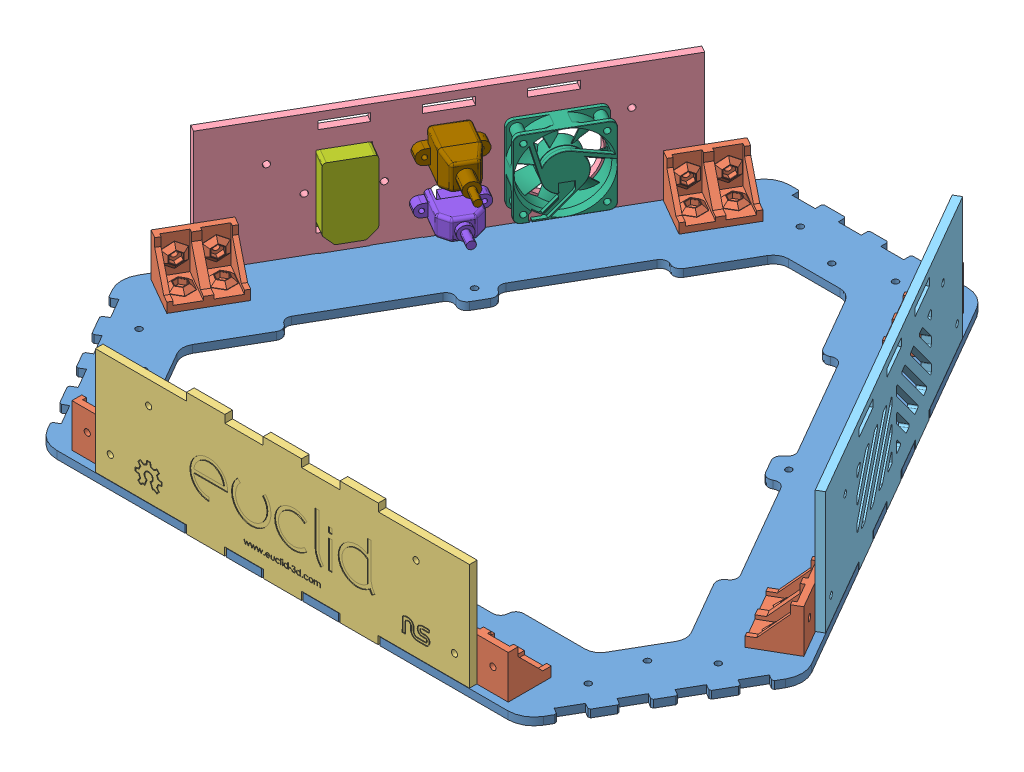
SolidWorks assembly bottom-assembly, configuration Default. Lengths in mm.
Overall size (489.42 85 494.01).
14 component instances, 9 part files, 42 mates.
Components (placement in the parent):
- acrylic-bottom-1: acrylic-bottom [Default] x (0 0 -1) z (1 0 0) size (388.46 5 443.29)
- window-bracket-dual-1: window-bracket-dual [Default] at (-122.1346 0 211.5433) x (0 0 -1) z (1 0 0) size (48.64 28 44.25)
- window-bracket-dual-2: window-bracket-dual [Default] x (0 0 -1) z (1 0 0) size (48.64 28 44.25)
- window-bracket-dual-3: window-bracket-dual [Default] x (0.866025 0 0.5) z (-0.5 0 0.866025) size (48.64 28 44.25)
- window-bracket-dual-4: window-bracket-dual [Default] at (-122.1346 0 -211.5433) x (0.866025 0 0.5) z (-0.5 0 0.866025) size (48.64 28 44.25)
- window-bracket-dual-5: window-bracket-dual [Default] at (244.2691 0 0) x (-0.866025 0 0.5) z (-0.5 0 -0.866025) size (48.64 28 44.25)
- window-bracket-dual-6: window-bracket-dual [Default] x (-0.866025 0 0.5) z (-0.5 0 -0.866025) size (48.64 28 44.25)
- acrylic-pscover-1: acrylic-pscover [Default] at (0 0 331.9134) x (0.866025 0 -0.5) z (0.5 0 0.866025) size (213.61 80 126.21)
- acrylic-switch-cover-1: acrylic-switch-cover [Default] x (0 0 -1) z (1 0 0) size (213.61 85 126.21)
- acrylic-bay-cover-1: acrylic-bay-cover [Default] x (0.866025 0 0.5) z (-0.5 0 0.866025) size (213.61 85 126.21)
- 50mm-fan-1: 50mm-fan [Default] at (-102.8673 -54.875 -118.7421) x (0 1 0) z (-0.5 0 0.866025) size (50.23 15.09 50)
- power-switch-1: power-switch [Default] at (-173.0529 -54.875 -42.1771) x (0.5 0 -0.866025) z (0 1 0) size (49.3 24.57 58)
- usb-b2b-extension-1: usb-b2b-extension [Default] at (-134.846 -69.75 -77.8534) x (-0.5 0 0.866025) z (-0.866025 0 -0.5) size (38 13.5 40)
- ethernet-extension-1: ethernet-extension [Default] at (-143.0732 -40 -82.6034) x (0.5 0 -0.866025) z (-0.866025 0 -0.5) size (36.4 22.5 53.25)
Mates (geometry in assembly coordinates):
- Coincident1: coincident anti-aligned: plane of acrylic-bottom-1 through (0 -90 0) normal (0 1 0); plane of window-bracket-dual-1 through (-185.75 -90 174.8149) normal (0 -1 0)
- Concentric1: concentric anti-aligned: cylinder of acrylic-bottom-1 through (-184.6346 -95 22.883) axis (0 1 0) radius 2; cylinder of window-bracket-dual-1 through (-184.6346 74.864 22.883) axis (0 -1 0) radius 2
- Concentric2: concentric anti-aligned: cylinder of acrylic-bottom-1 through (-194.6346 -95 40.2035) axis (0 1 0) radius 2; cylinder of window-bracket-dual-1 through (-194.6346 74.864 40.2035) axis (0 -1 0) radius 2
- Coincident2: coincident anti-aligned: plane of acrylic-bottom-1 through (0 -90 0) normal (0 1 0); plane of window-bracket-dual-2 through (-63.6154 -90 -36.7284) normal (0 -1 0)
- Concentric3: concentric anti-aligned: cylinder of acrylic-bottom-1 through (-62.5 -95 -188.6603) axis (0 1 0) radius 2; cylinder of window-bracket-dual-2 through (-62.5 74.864 -188.6603) axis (0 -1 0) radius 2
- Concentric4: concentric anti-aligned: cylinder of acrylic-bottom-1 through (-72.5 -95 -171.3397) axis (0 1 0) radius 2; cylinder of window-bracket-dual-2 through (-72.5 74.864 -171.3397) axis (0 -1 0) radius 2
- Coincident3: coincident anti-aligned: plane of acrylic-bottom-1 through (0 -90 0) normal (0 1 0); plane of window-bracket-dual-4 through (-58.5192 -90 -248.2716) normal (0 -1 0)
- Concentric5: concentric anti-aligned: cylinder of acrylic-bottom-1 through (72.5 -95 -171.3397) axis (0 1 0) radius 2; cylinder of window-bracket-dual-4 through (72.5 74.864 -171.3397) axis (0 -1 0) radius 2
- Concentric6: concentric anti-aligned: cylinder of acrylic-bottom-1 through (62.5 -95 -188.6603) axis (0 1 0) radius 2; cylinder of window-bracket-dual-4 through (62.5 74.864 -188.6603) axis (0 -1 0) radius 2
- Coincident4: coincident anti-aligned: plane of acrylic-bottom-1 through (0 -90 0) normal (0 1 0); plane of window-bracket-dual-3 through (63.6154 -90 -36.7284) normal (0 -1 0)
- Concentric7: concentric anti-aligned: cylinder of acrylic-bottom-1 through (194.6346 -95 40.2035) axis (0 1 0) radius 2; cylinder of window-bracket-dual-3 through (194.6346 74.864 40.2035) axis (0 -1 0) radius 2
- Concentric8: concentric anti-aligned: cylinder of acrylic-bottom-1 through (184.6346 -95 22.883) axis (0 1 0) radius 2; cylinder of window-bracket-dual-3 through (184.6346 74.864 22.883) axis (0 -1 0) radius 2
- Coincident5: coincident anti-aligned: plane of acrylic-bottom-1 through (0 -90 0) normal (0 1 0); plane of window-bracket-dual-5 through (244.2691 -90 73.4567) normal (0 -1 0)
- Concentric9: concentric anti-aligned: cylinder of acrylic-bottom-1 through (112.1346 -95 148.4567) axis (0 1 0) radius 2; cylinder of window-bracket-dual-5 through (112.1346 74.864 148.4567) axis (0 -1 0) radius 2
- Concentric10: concentric anti-aligned: cylinder of acrylic-bottom-1 through (132.1346 -95 148.4567) axis (0 1 0) radius 2; cylinder of window-bracket-dual-5 through (132.1346 74.864 148.4567) axis (0 -1 0) radius 2
- Coincident6: coincident anti-aligned: plane of acrylic-bottom-1 through (0 -90 0) normal (0 1 0); plane of window-bracket-dual-6 through (0 -90 73.4567) normal (0 -1 0)
- Concentric11: concentric anti-aligned: cylinder of acrylic-bottom-1 through (-112.1346 -95 148.4567) axis (0 1 0) radius 2; cylinder of window-bracket-dual-6 through (-112.1346 74.864 148.4567) axis (0 -1 0) radius 2
- Concentric12: concentric anti-aligned: cylinder of acrylic-bottom-1 through (-132.1346 -95 148.4567) axis (0 1 0) radius 2; cylinder of window-bracket-dual-6 through (-132.1346 74.864 148.4567) axis (0 -1 0) radius 2
- Coincident8: coincident aligned: plane of acrylic-bottom-1; plane of assembly through (0 0 0) normal (0 1 0)
- Coincident10: coincident anti-aligned: plane of acrylic-bottom-1 through (0 0 0) normal (0 0 -1); plane of assembly through (0 0 0) normal (0 0 1)
- Coincident11: coincident aligned: plane of acrylic-bottom-1 through (0 0 0) normal (1 0 0); plane of assembly through (0 0 0) normal (1 0 0)
- Coincident12: coincident anti-aligned: plane of window-bracket-dual-5 through (244.2691 0 163.4567) normal (0 0 1); plane of acrylic-pscover-1 through (0 0 163.4567) normal (0 0 -1)
- Concentric13: concentric aligned: cylinder of window-bracket-dual-5 through (112.1346 -75 -1.4073) axis (0 0 1) radius 2; cylinder of acrylic-pscover-1 through (112.1346 -75 95.5709) axis (0 0 1) radius 2
- Concentric14: concentric aligned: cylinder of window-bracket-dual-6 through (-112.1346 -75 -1.4073) axis (0 0 1) radius 2; cylinder of acrylic-pscover-1 through (-112.1346 -75 95.5709) axis (0 0 1) radius 2
- Coincident13: coincident anti-aligned: plane of window-bracket-dual-3 through (141.5577 0 -81.7284) normal (0.866025 0 -0.5); plane of acrylic-bay-cover-1 through (141.5577 0 -81.7284) normal (-0.866025 0 0.5)
- Concentric15: concentric anti-aligned: cylinder of window-bracket-dual-4 through (-57.286 -75 -96.4077) axis (0.866025 0 -0.5) radius 2; cylinder of acrylic-bay-cover-1 through (148.6114 -75 -215.2827) axis (-0.866025 0 0.5) radius 2
- Concentric16: concentric anti-aligned: cylinder of window-bracket-dual-3 through (54.8485 -75 97.815) axis (0.866025 0 -0.5) radius 2; cylinder of acrylic-bay-cover-1 through (260.7459 -75 -21.0599) axis (-0.866025 0 0.5) radius 2
- Coincident14: coincident anti-aligned: plane of window-bracket-dual-2 through (-141.5577 0 -81.7284) normal (-0.866025 0 -0.5); plane of acrylic-switch-cover-1 through (-141.5577 0 -81.7284) normal (0.866025 0 0.5)
- Concentric17: concentric anti-aligned: cylinder of window-bracket-dual-2 through (57.286 -75 -96.4077) axis (-0.866025 0 -0.5) radius 2; cylinder of acrylic-switch-cover-1 through (-148.6114 -75 -215.2827) axis (0.866025 0 0.5) radius 2
- Concentric18: concentric anti-aligned: cylinder of window-bracket-dual-1 through (-54.8485 -75 97.815) axis (-0.866025 0 -0.5) radius 2; cylinder of acrylic-switch-cover-1 through (-260.7459 -75 -21.0599) axis (0.866025 0 0.5) radius 2
- Coincident15: coincident anti-aligned: plane of acrylic-switch-cover-1 through (-141.5577 0 -81.7284) normal (0.866025 0 0.5); plane of 50mm-fan-1 through (-103.3577 -79.875 -147.8927) normal (-0.866025 0 -0.5)
- Concentric19: concentric anti-aligned: cylinder of acrylic-switch-cover-1 through (-34.4442 -34.875 -56.144) axis (-0.866025 0 -0.5) radius 1.6; cylinder of 50mm-fan-1 through (-130.3892 -34.875 -111.5379) axis (0.866025 0 0.5) radius 1.85
- Concentric21: concentric anti-aligned: cylinder of acrylic-switch-cover-1 through (-14.4442 -74.875 -90.785) axis (-0.866025 0 -0.5) radius 1.6; cylinder of 50mm-fan-1 through (-110.3892 -74.875 -146.1789) axis (0.866025 0 0.5) radius 1.85
- Concentric22: concentric aligned: cylinder of acrylic-switch-cover-1 through (-84.6942 -54.875 30.8916) axis (-0.866025 0 -0.5) radius 2; cylinder of power-switch-1 through (-180.4378 -54.875 -24.386) axis (-0.866025 0 -0.5) radius 2
- Concentric23: concentric aligned: cylinder of acrylic-switch-cover-1 through (-65.5942 -54.875 -2.1906) axis (-0.866025 0 -0.5) radius 2; cylinder of power-switch-1 through (-161.3378 -54.875 -57.4682) axis (-0.866025 0 -0.5) radius 2
- Coincident17: coincident anti-aligned: plane of acrylic-switch-cover-1 through (-145.8878 0 -84.2284) normal (-0.866025 0 -0.5); plane of power-switch-1 through (-170.8878 -54.875 -40.9271) normal (0.866025 0 0.5)
- Coincident18: coincident anti-aligned: plane of acrylic-switch-cover-1 through (-141.5577 0 -81.7284) normal (0.866025 0 0.5); plane of usb-b2b-extension-1 through (-151.0577 -63 -65.2739) normal (-0.866025 0 -0.5)
- Coincident19: coincident anti-aligned: plane of acrylic-switch-cover-1 through (-141.5577 0 -81.7284) normal (0.866025 0 0.5); plane of ethernet-extension-1 through (-148.3077 -40 -70.037) normal (-0.866025 0 -0.5)
- Concentric31: concentric aligned: cylinder of acrylic-switch-cover-1 through (-42.6442 -69.75 -41.9412) axis (-0.866025 0 -0.5) radius 1.6; cylinder of usb-b2b-extension-1 through (-111.108 -69.75 -81.4687) axis (-0.866025 0 -0.5) radius 1.5
- Concentric32: concentric aligned: cylinder of acrylic-switch-cover-1 through (-57.6442 -69.75 -15.9604) axis (-0.866025 0 -0.5) radius 1.6; cylinder of usb-b2b-extension-1 through (-126.108 -69.75 -55.488) axis (-0.866025 0 -0.5) radius 1.5
- Concentric33: concentric aligned: cylinder of acrylic-switch-cover-1 through (-43.3942 -40 -40.6421) axis (-0.866025 0 -0.5) radius 1.6; cylinder of ethernet-extension-1 through (-128.962 -40 -90.0447) axis (-0.866025 0 -0.5) radius 1.5
- Concentric34: concentric aligned: cylinder of acrylic-switch-cover-1 through (-56.8942 -40 -17.2594) axis (-0.866025 0 -0.5) radius 1.6; cylinder of ethernet-extension-1 through (-142.462 -40 -66.662) axis (-0.866025 0 -0.5) radius 1.5
